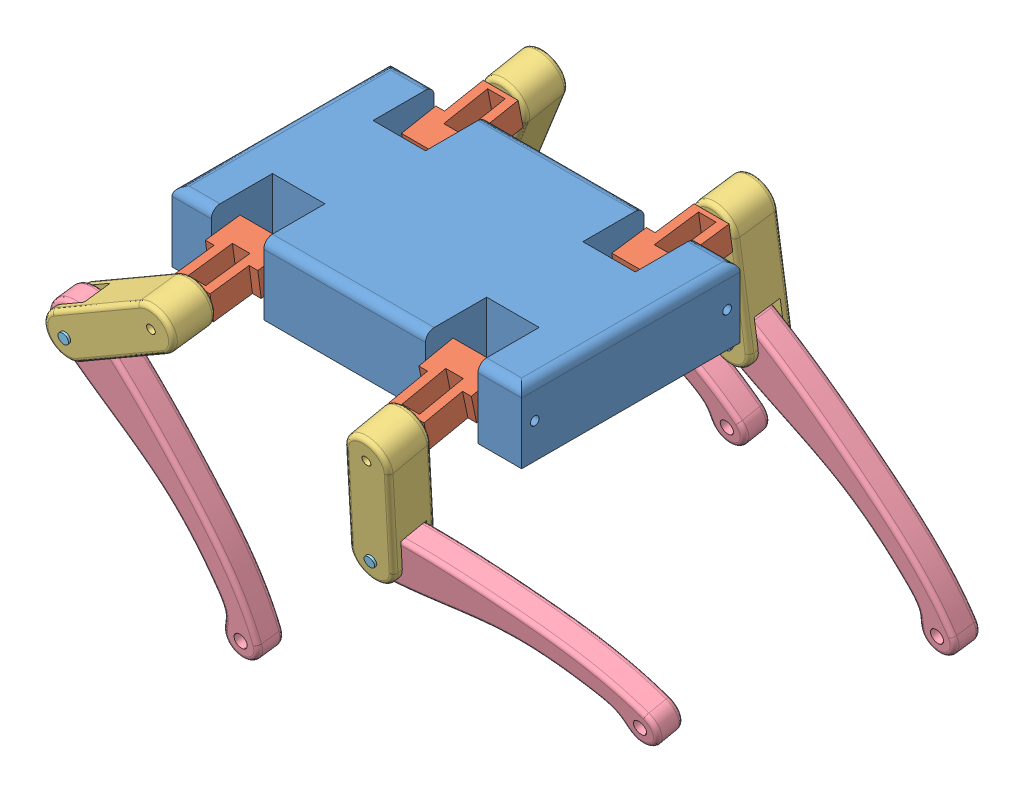
SolidWorks assembly Ensamblaje1, configuration Predeterminado. Lengths in mm.
Overall size (72.61 41.99 51.25).
18 component instances, 6 part files, 33 mates.
Components (placement in the parent):
- Pieza4-1: Pieza4 [Predeterminado] at (7.5189 -6.3271 28.5) x (-1 0 0) z (0 1 0) size (40 25 8)
- Pieza1-1: Pieza1 [Predeterminado] at (-24.9811 -1.3566 56.1586) x (0 0.129234 -0.991614) z (0 -0.991614 -0.129234) size (11 11 3)
- Pieza1-2: Pieza1 [Predeterminado] at (-0.4811 -4.6155 55.6056) x (0 0.205083 -0.978745) z (0 0.978745 0.205083) size (11 11 3)
- Pieza1-3: Pieza1 [Predeterminado] at (-24.4811 -0.1042 26.3536) x (0 -0.187358 0.982292) z (0 -0.982292 -0.187358) size (11 11 3)
- Pieza1-4: Pieza1 [Predeterminado] at (-0.4811 -0.2828 26.2506) x (0 -0.139743 0.990188) z (0 -0.990188 -0.139743) size (11 11 3)
- Pieza2-3: Pieza2 [Predeterminado] at (-24.9811 -3.1671 58.4437) x (0.525849 -0.843445 -0.109924) z (0 -0.129234 0.991614) size (5 17.5 5)
- Pieza2-4: Pieza2 [Predeterminado] at (-0.4811 -3.6601 58.3601) x (0.987635 -0.15344 -0.032151) z (0 -0.205083 0.978745) size (5 17.5 5)
- Pieza2-5: Pieza2 [Predeterminado] at (-24.4811 -0.1725 18.7054) x (0.893529 -0.441054 -0.084125) z (0 -0.187358 0.982292) size (5 17.5 5)
- Pieza2-6: Pieza2 [Predeterminado] at (-0.4811 -0.72 18.6146) x (0.999953 -0.009637 -0.00136) z (0 -0.139743 0.990188) size (5 17.5 5)
- Pieza3-1: Pieza3 [Predeterminado] at (-35.6134 -9.8143 58.5859) x (0.673084 -0.733364 -0.095577) z (0 -0.129234 0.991614) size (33.85 12.42 5.21)
- Pieza3-3: Pieza3 [Predeterminado] at (-2.4408 -15.9482 56.807) x (0.998285 0.057302 0.012007) z (0 -0.205083 0.978745) size (33.85 12.42 5.21)
- Pieza3-4: Pieza3 [Predeterminado] at (-0.6028 -13.2365 17.8581) x (0.793365 -0.602774 -0.085068) z (0 -0.139743 0.990188) size (33.85 12.42 5.21)
- Pieza3-6: Pieza3 [Predeterminado] at (-30.0937 -11.3311 17.5951) x (0.937871 -0.340839 -0.06501) z (0 -0.187358 0.982292) size (33.85 12.42 5.21)
- Pieza6^Ensamblaje1-1: Pieza6^Ensamblaje1 [Predeterminado] at origin (virtual)
- Pieza5-1: Pieza5 [Predeterminado] at (-0.6028 -13.0968 16.8679) x (1 0 0) z (0 -0.139743 0.990188) size (1.2 1.2 5.5)
- Pieza5-2: Pieza5 [Predeterminado] at (-30.0937 -11.1438 16.6128) x (1 0 0) z (0 -0.187358 0.982292) size (1.2 1.2 5.5)
- Pieza5-3: Pieza5 [Predeterminado] at (-35.6134 -9.6851 57.5943) x (1 0 0) z (0 -0.129234 0.991614) size (1.2 1.2 5.5)
- Pieza5-4: Pieza5 [Predeterminado] at (-2.4408 -15.7431 55.8283) x (1 0 0) z (0 -0.205083 0.978745) size (1.2 1.2 5.5)
Mates (geometry in assembly coordinates):
- Paralelo1: parallel: plane of assembly through (-28.4811 0 0) normal (-1 0 0); plane of Pieza4-1 through (-27.9811 1.6729 46.5) normal (1 0 0); plane of assembly
- Concéntrica1: concentric anti-aligned: cylinder of Pieza1-1 through (-30.4811 -2.3271 51.9982) axis (1 0 0) radius 0.5
- Coincidente3: coincident anti-aligned: plane of Pieza4-1 through (-27.9811 1.6729 46.5) normal (1 0 0); plane of Pieza1-1 through (-27.9811 -3.556 49.8212) normal (-1 0 0)
- Concéntrica2: concentric aligned: cylinder of Pieza1-2 through (5.0189 -2.3271 51.9982) axis (-1 0 0) radius 0.5
- Coincidente4: coincident anti-aligned: plane of Pieza4-1 through (2.5189 1.6729 53.5) normal (-1 0 0); plane of Pieza1-2 through (2.5189 -0.4488 50.3484) normal (1 0 0)
- Concéntrica3: concentric aligned: cylinder of Pieza1-4 through (5.0189 -2.3271 30.0018) axis (-1 0 0) radius 0.5
- Coincidente5: coincident anti-aligned: plane of Pieza4-1 through (2.5189 1.6729 28.5) normal (-1 0 0); plane of Pieza1-4 through (2.5189 -4.0918 31.7725) normal (1 0 0)
- Concéntrica4: concentric aligned: cylinder of Pieza1-3 through (-18.9811 -2.3271 30.0018) axis (-1 0 0) radius 0.5
- Coincidente6: coincident anti-aligned: plane of Pieza4-1 through (-27.4811 1.6729 35.5) normal (1 0 0); plane of Pieza1-3 through (-27.4811 -3.4258 27.7561) normal (-1 0 0)
- Concéntrica5: concentric aligned: cylinder of Pieza1-1 through (-24.9811 -3.4902 60.9228) axis (0 0.129234 -0.991614) radius 0.5; cylinder of Pieza2-3 through (-24.9811 -3.8133 63.4018) axis (0 0.129234 -0.991614) radius 0.5
- Concéntrica6: concentric aligned: cylinder of Pieza1-2 through (-0.4811 -4.1728 60.8069) axis (0 0.205083 -0.978745) radius 0.5; cylinder of Pieza2-4 through (-0.4811 -4.6855 63.2538) axis (0 0.205083 -0.978745) radius 0.5
- Concéntrica7: concentric anti-aligned: cylinder of Pieza1-3 through (-24.4811 -0.6409 21.1611) axis (0 -0.187358 0.982292) radius 0.5; cylinder of Pieza2-5 through (-24.4811 -1.1093 23.6169) axis (0 0.187358 -0.982292) radius 0.5
- Concéntrica8: concentric anti-aligned: cylinder of Pieza1-4 through (-0.4811 -1.0694 21.0901) axis (0 -0.139743 0.990188) radius 0.5; cylinder of Pieza2-6 through (-0.4811 -1.4187 23.5655) axis (0 0.139743 -0.990188) radius 0.5
- Coincidente7: coincident anti-aligned: plane of Pieza1-1 through (-26.9811 -4.6545 58.2499) normal (0 -0.129234 0.991614); plane of Pieza2-3 through (-24.9811 -3.1671 58.4437) normal (0 0.129234 -0.991614)
- Coincidente8: coincident anti-aligned: plane of Pieza1-2 through (1.5189 -2.192 58.6677) normal (0 -0.205083 0.978745); plane of Pieza2-4 through (-0.4811 -3.6601 58.3601) normal (0 0.205083 -0.978745)
- Coincidente9: coincident anti-aligned: plane of Pieza1-4 through (1.5189 -2.904 23.3559) normal (0 0.139743 -0.990188); plane of Pieza2-6 through (-0.4811 -1.4187 23.5655) normal (0 -0.139743 0.990188)
- Coincidente10: coincident anti-aligned: plane of Pieza1-3 through (-22.4811 -2.5827 23.3358) normal (0 0.187358 -0.982292); plane of Pieza2-5 through (-24.4811 -1.1093 23.6169) normal (0 -0.187358 0.982292)
- Concéntrica9: concentric aligned: cylinder of Pieza2-6 through (-0.6028 -13.7955 21.8188) axis (0 0.139743 -0.990188) radius 0.5; cylinder of Pieza5-1 through (-0.6028 -13.7955 21.8188) axis (0 0.139743 -0.990188) radius 0.5
- Coincidente11: coincident anti-aligned: plane of Pieza2-6 through (-0.4811 -1.4187 23.5655) normal (0 -0.139743 0.990188); plane of Pieza5-1 through (-0.6028 -13.7955 21.8188) normal (0 0.139743 -0.990188)
- Concéntrica10: concentric aligned: cylinder of Pieza2-5 through (-30.0937 -12.0806 21.5242) axis (0 0.187358 -0.982292) radius 0.5; cylinder of Pieza5-2 through (-30.0937 -12.0806 21.5242) axis (0 0.187358 -0.982292) radius 0.5
- Coincidente12: coincident anti-aligned: plane of Pieza2-5 through (-24.4811 -1.1093 23.6169) normal (0 -0.187358 0.982292); plane of Pieza5-2 through (-30.0937 -12.0806 21.5242) normal (0 0.187358 -0.982292)
- Concéntrica11: concentric aligned: cylinder of Pieza2-4 through (-2.4408 -16.7686 60.722) axis (0 0.205083 -0.978745) radius 0.5; cylinder of Pieza5-4 through (-2.4408 -16.7686 60.722) axis (0 0.205083 -0.978745) radius 0.5
- Coincidente13: coincident anti-aligned: plane of Pieza2-4 through (-0.4811 -4.6855 63.2538) normal (0 -0.205083 0.978745); plane of Pieza5-4 through (-2.4408 -16.7686 60.722) normal (0 0.205083 -0.978745)
- Concéntrica12: concentric aligned: cylinder of Pieza2-3 through (-35.6134 -10.3313 62.5523) axis (0 0.129234 -0.991614) radius 0.5; cylinder of Pieza5-3 through (-35.6134 -10.3313 62.5523) axis (0 0.129234 -0.991614) radius 0.5
- Coincidente14: coincident anti-aligned: plane of Pieza2-3 through (-24.9811 -3.8133 63.4018) normal (0 -0.129234 0.991614); plane of Pieza5-3 through (-35.6134 -10.3313 62.5523) normal (0 0.129234 -0.991614)
- Concéntrica13: concentric aligned: cylinder of Pieza3-4 through (-0.6028 -13.6558 20.8286) axis (0 0.139743 -0.990188) radius 0.5; cylinder of Pieza5-1 through (-0.6028 -13.7955 21.8188) axis (0 0.139743 -0.990188) radius 0.5
- Coincidente15: coincident anti-aligned: plane of Pieza2-6 through (-2.981 -0.8357 19.6082) normal (0 -0.139743 0.990188); plane of Pieza3-4 through (-0.6028 -13.2365 17.8581) normal (0 0.139743 -0.990188)
- Concéntrica14: concentric aligned: cylinder of Pieza3-6 through (-30.0937 -11.8932 20.5419) axis (0 0.187358 -0.982292) radius 0.5; cylinder of Pieza5-2 through (-30.0937 -12.0806 21.5242) axis (0 0.187358 -0.982292) radius 0.5
- Coincidente16: coincident anti-aligned: plane of Pieza2-5 through (-26.715 0.1807 22.8449) normal (0 0.187358 -0.982292); plane of Pieza3-6 through (-30.0937 -11.8932 20.5419) normal (0 -0.187358 0.982292)
- Concéntrica15: concentric aligned: cylinder of Pieza3-3 through (-2.4408 -16.5635 59.7432) axis (0 0.205083 -0.978745) radius 0.5; cylinder of Pieza5-4 through (-2.4408 -16.7686 60.722) axis (0 0.205083 -0.978745) radius 0.5
- Coincidente17: coincident anti-aligned: plane of Pieza2-4 through (-2.9502 -3.4816 59.4192) normal (0 -0.205083 0.978745); plane of Pieza3-3 through (-2.4408 -15.9482 56.807) normal (0 0.205083 -0.978745)
- Concéntrica16: concentric aligned: cylinder of Pieza3-1 through (-35.6134 -10.202 61.5607) axis (0 0.129234 -0.991614) radius 0.5; cylinder of Pieza5-3 through (-35.6134 -10.3313 62.5523) axis (0 0.129234 -0.991614) radius 0.5
- Coincidente18: coincident anti-aligned: plane of Pieza2-3 through (-26.2958 -1.1877 59.7102) normal (0 -0.129234 0.991614); plane of Pieza3-1 through (-35.6134 -9.8143 58.5859) normal (0 0.129234 -0.991614)
